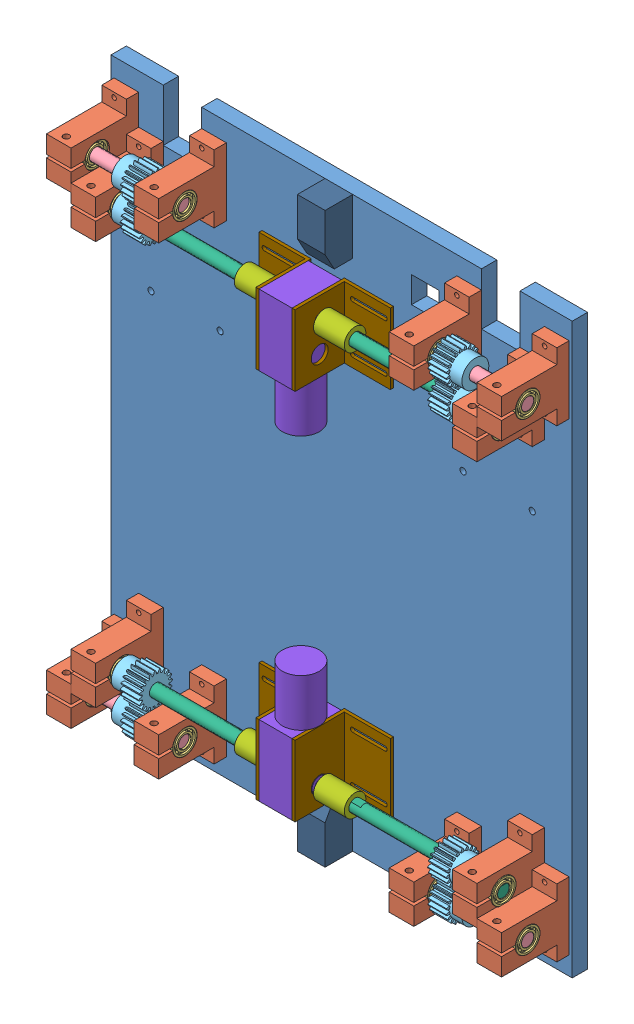
SolidWorks assembly 装配体1, configuration 默认. Lengths in mm.
Overall size (300 370 54).
64 component instances, 10 part files, 32 mates.
Components (placement in the parent):
- 坐垫-1: 坐垫 [默认] at (-124.3252 -195.4572 365) size (300 370 10)
- 光轴支架-1: 光轴支架 [默认] at (-142.3271 -143.8242 371.8767) x (0 -1 0) z (-1 0 0) size (44 44 16)
- deep groove ball bearings gb-1: deep groove ball bearings gb [Rolling bearings 618-8 GB 276-94] at (-145.2035 -140.9025 402) x (-1 0 0) z (0 -0.927196 -0.374576) size (4 16 16)
- am8-1: am8 [默认] at (-86.5971 -156.6197 405.6451) x (0 -0.279688 0.960091) z (-1 0 0) size (8 8 71.73)
- spur gear_gb-1: spur gear_gb [GB - Spur gear 1M 20T 20PA 12FW ---S20B75H20L8.0N] at (-116.3271 -140.9025 402) x (1 0 0) z (0 0.809131 -0.587628) size (20 21.8 21.8)
- 光轴支架-2: 光轴支架 [默认] at (-142.3271 -118.2309 371.8767) x (0 1 0) z (1 0 0) size (44 44 16)
- deep groove ball bearings gb-2: deep groove ball bearings gb [Rolling bearings 618-8 GB 276-94] at (-129.0651 -121.1525 402) size (4 16 16)
- M8光轴连接齿轮-1: M8光轴连接齿轮 [默认] at (-142.3271 -136.3515 404.7888) x (0 0 -1) z (1 0 0) size (8 8 104.25)
- deep groove ball bearings gb-3: deep groove ball bearings gb [Rolling bearings 618-8 GB 276-94] at (-140.8939 -121.1525 402) size (4 16 16)
- deep groove ball bearings gb-4: deep groove ball bearings gb [Rolling bearings 618-8 GB 276-94] at (-156.497 -140.9025 402) x (-1 0 0) z (0 -0.924225 -0.381849) size (4 16 16)
- 联轴器-1: 联轴器 [默认] at (-26.0771 -121.1525 402) x (0 0.642544 -0.766249) z (-1 0 0) size (14 14 20)
- 双输出涡轮蜗杆电机-1: 双输出涡轮蜗杆电机 [默认] at (-27.3331 -113.7996 418) x (0 1 0) z (0 0 -1) size (76.8 52.5 32)
- 零件1-1: 零件1 [默认] at (-21.0771 -118.3588 384) x (0 -1 0) z (-1 0 0) size (46 34 32)
- spur gear_gb-5: spur gear_gb [GB - Spur gear 1M 20T 20PA 12FW ---S20B75H20L8.0N] at (-116.3271 -121.1525 402) x (1 0 0) z (0 -0.733673 0.679503) size (20 21.8 21.8)
- 光轴支架-3: 光轴支架 [默认] at (-85.2921 -143.8242 371.8767) x (0 -1 0) z (-1 0 0) size (44 44 16)
- deep groove ball bearings gb-7: deep groove ball bearings gb [Rolling bearings 618-8 GB 276-94] at (-87.2921 -140.9025 402) x (-1 0 0) z (0 -0.924225 -0.381849) size (4 16 16)
- deep groove ball bearings gb-8: deep groove ball bearings gb [Rolling bearings 618-8 GB 276-94] at (-99.2921 -140.9025 402) size (4 16 16)
- 光轴支架-4: 光轴支架 [默认] at (137.6729 -143.8242 371.8767) x (0 -1 0) z (-1 0 0) size (44 44 16)
- deep groove ball bearings gb-9: deep groove ball bearings gb [Rolling bearings 618-8 GB 276-94] at (124.5493 -140.9025 402) x (1 0 0) z (0 0.927196 0.374576) size (4 16 16)
- deep groove ball bearings gb-10: deep groove ball bearings gb [Rolling bearings 618-8 GB 276-94] at (120.2398 -121.1525 402) x (-1 0 0) z (0 0 -1) size (4 16 16)
- am8-2: am8 [默认] at (137.6729 -156.6197 405.6451) x (0 -0.279688 0.960091) z (-1 0 0) size (8 8 71.73)
- spur gear_gb-2: spur gear_gb [GB - Spur gear 1M 20T 20PA 12FW ---S20B75H20L8.0N] at (95.6729 -140.9025 402) x (-1 0 0) z (0 -0.809131 0.587628) size (20 21.8 21.8)
- 光轴支架-5: 光轴支架 [默认] at (105.6729 -118.2309 371.8767) x (0 1 0) z (1 0 0) size (44 44 16)
- M8光轴连接齿轮-2: M8光轴连接齿轮 [默认] at (17.4229 -136.3515 404.7888) x (0 0 -1) z (1 0 0) size (8 8 104.25)
- deep groove ball bearings gb-11: deep groove ball bearings gb [Rolling bearings 618-8 GB 276-94] at (108.411 -121.1525 402) x (-1 0 0) z (0 0 -1) size (4 16 16)
- deep groove ball bearings gb-12: deep groove ball bearings gb [Rolling bearings 618-8 GB 276-94] at (135.8428 -140.9025 402) x (1 0 0) z (0 0.924225 0.381849) size (4 16 16)
- spur gear_gb-6: spur gear_gb [GB - Spur gear 1M 20T 20PA 12FW ---S20B75H20L8.0N] at (95.6729 -121.1525 402) x (-1 0 0) z (0 0.733673 -0.679503) size (20 21.8 21.8)
- deep groove ball bearings gb-13: deep groove ball bearings gb [Rolling bearings 618-8 GB 276-94] at (66.6379 -140.9025 402) x (1 0 0) z (0 0.924225 0.381849) size (4 16 16)
- 光轴支架-6: 光轴支架 [默认] at (80.6379 -143.8242 371.8767) x (0 -1 0) z (-1 0 0) size (44 44 16)
- deep groove ball bearings gb-14: deep groove ball bearings gb [Rolling bearings 618-8 GB 276-94] at (78.6379 -140.9025 402) x (-1 0 0) z (0 0 -1) size (4 16 16)
- 零件1-2: 零件1 [默认] at (0.4229 -103.9462 384) x (0 1 0) z (1 0 0) size (46 34 32)
- 联轴器-2: 联轴器 [默认] at (5.4229 -121.1525 402) x (0 -0.642544 0.766249) z (1 0 0) size (14 14 20)
- 光轴支架-13: 光轴支架 [默认] at (-158.3271 164.0191 371.8767) x (0 1 0) z (1 0 0) size (44 44 16)
- deep groove ball bearings gb-27: deep groove ball bearings gb [Rolling bearings 618-8 GB 276-94] at (-156.497 161.0975 402) x (-1 0 0) z (0 -0.924225 0.381849) size (4 16 16)
- deep groove ball bearings gb-28: deep groove ball bearings gb [Rolling bearings 618-8 GB 276-94] at (-145.2035 161.0975 402) x (-1 0 0) z (0 -0.927196 0.374576) size (4 16 16)
- am8-5: am8 [默认] at (-158.3271 176.8147 405.6451) x (0 0.279688 0.960091) z (1 0 0) size (8 8 71.73)
- 光轴支架-14: 光轴支架 [默认] at (-126.3271 138.4258 371.8767) x (0 -1 0) z (-1 0 0) size (44 44 16)
- deep groove ball bearings gb-29: deep groove ball bearings gb [Rolling bearings 618-8 GB 276-94] at (-140.8939 141.3475 402) x (1 0 0) z (0 0 -1) size (4 16 16)
- deep groove ball bearings gb-30: deep groove ball bearings gb [Rolling bearings 618-8 GB 276-94] at (-129.0651 141.3475 402) x (1 0 0) z (0 0 -1) size (4 16 16)
- spur gear_gb-9: spur gear_gb [GB - Spur gear 1M 20T 20PA 12FW ---S20B75H20L8.0N] at (-116.3271 141.3475 402) x (1 0 0) z (0 -0.733673 -0.679503) size (20 21.8 21.8)
- M8光轴连接齿轮-5: M8光轴连接齿轮 [默认] at (-38.0771 156.5465 404.7888) x (0 0 -1) z (-1 0 0) size (8 8 104.25)
- spur gear_gb-10: spur gear_gb [GB - Spur gear 1M 20T 20PA 12FW ---S20B75H20L8.0N] at (-116.3271 161.0975 402) x (1 0 0) z (0 0.809131 0.587628) size (20 21.8 21.8)
- 光轴支架-15: 光轴支架 [默认] at (-101.2921 164.0191 371.8767) x (0 1 0) z (1 0 0) size (44 44 16)
- deep groove ball bearings gb-31: deep groove ball bearings gb [Rolling bearings 618-8 GB 276-94] at (-99.2921 161.0975 402) x (1 0 0) z (0 0 -1) size (4 16 16)
- deep groove ball bearings gb-32: deep groove ball bearings gb [Rolling bearings 618-8 GB 276-94] at (-87.2921 161.0975 402) x (-1 0 0) z (0 -0.924225 0.381849) size (4 16 16)
- 零件1-5: 零件1 [默认] at (-21.0771 124.1412 384) x (0 -1 0) z (-1 0 0) size (46 34 32)
- 联轴器-5: 联轴器 [默认] at (-26.0771 141.3475 402) x (0 0.642544 0.766249) z (-1 0 0) size (14 14 20)
- 零件1-6: 零件1 [默认] at (0.4229 138.5538 384) x (0 1 0) z (1 0 0) size (46 34 32)
- 联轴器-6: 联轴器 [默认] at (5.4229 141.3475 402) x (0 -0.642544 -0.766249) z (1 0 0) size (14 14 20)
- M8光轴连接齿轮-6: M8光轴连接齿轮 [默认] at (121.6729 156.5465 404.7888) x (0 0 -1) z (-1 0 0) size (8 8 104.25)
- 光轴支架-16: 光轴支架 [默认] at (121.6729 138.4258 371.8767) x (0 -1 0) z (-1 0 0) size (44 44 16)
- spur gear_gb-11: spur gear_gb [GB - Spur gear 1M 20T 20PA 12FW ---S20B75H20L8.0N] at (95.6729 141.3475 402) x (-1 0 0) z (0 0.733673 0.679503) size (20 21.8 21.8)
- deep groove ball bearings gb-33: deep groove ball bearings gb [Rolling bearings 618-8 GB 276-94] at (108.411 141.3475 402) x (-1 0 0) z (0 0 1) size (4 16 16)
- deep groove ball bearings gb-34: deep groove ball bearings gb [Rolling bearings 618-8 GB 276-94] at (120.2398 141.3475 402) x (-1 0 0) z (0 0 1) size (4 16 16)
- am8-6: am8 [默认] at (65.9429 176.8147 405.6451) x (0 0.279688 0.960091) z (1 0 0) size (8 8 71.73)
- 光轴支架-17: 光轴支架 [默认] at (121.6729 164.0191 371.8767) x (0 1 0) z (1 0 0) size (44 44 16)
- 光轴支架-18: 光轴支架 [默认] at (64.6379 164.0191 371.8767) x (0 1 0) z (1 0 0) size (44 44 16)
- spur gear_gb-12: spur gear_gb [GB - Spur gear 1M 20T 20PA 12FW ---S20B75H20L8.0N] at (95.6729 161.0975 402) x (-1 0 0) z (0 -0.809131 -0.587628) size (20 21.8 21.8)
- deep groove ball bearings gb-35: deep groove ball bearings gb [Rolling bearings 618-8 GB 276-94] at (78.6379 161.0975 402) x (-1 0 0) z (0 0 1) size (4 16 16)
- deep groove ball bearings gb-36: deep groove ball bearings gb [Rolling bearings 618-8 GB 276-94] at (66.6379 161.0975 402) x (1 0 0) z (0 0.924225 -0.381849) size (4 16 16)
- 双输出涡轮蜗杆电机-3: 双输出涡轮蜗杆电机 [默认] at (-27.3331 133.9946 386) x (0 -1 0) z (0 0 1) size (76.8 52.5 32)
- deep groove ball bearings gb-37: deep groove ball bearings gb [Rolling bearings 618-8 GB 276-94] at (135.8428 161.0975 402) x (1 0 0) z (0 0.924225 -0.381849) size (4 16 16)
- 接近开关-1: 接近开关 [默认] at (-3.0771 -170.4461 383.327) x (0 -1 0) z (-1 0 0) size (36 18 18)
- 接近开关-2: 接近开关 [默认] at (-21.0771 190.6411 383.327) x (0 1 0) z (1 0 0) size (36 18 18)
Mates (geometry in assembly coordinates):
- 同心1: concentric anti-aligned: cylinder of 坐垫-1 through (-150.3271 -159.9025 365) axis (0 0 1) radius 1.5; cylinder of 光轴支架-1 through (-150.3271 -159.9025 414) axis (0 0 -1) radius 1.5
- 重合1: coincident anti-aligned: plane of 坐垫-1 through (-124.3252 -195.4572 375) normal (0 0 1); plane of 光轴支架-1 through (-158.3271 -118.9025 375) normal (0 0 -1)
- 同心21: concentric aligned: cylinder of 光轴支架-1 through (-158.3271 -140.9025 402) axis (1 0 0) radius 8; cylinder of deep groove ball bearings gb-1 through (-138.2321 -140.9025 402) axis (1 0 0) radius 4
- 同心3: concentric aligned: cylinder of deep groove ball bearings gb-1 through (-138.2321 -140.9025 402) axis (1 0 0) radius 4; cylinder of am8-1 through (-158.3271 -140.9025 402) axis (1 0 0) radius 4
- 同心4: concentric anti-aligned: cylinder of am8-1 through (-158.3271 -140.9025 402) axis (1 0 0) radius 4; cylinder of spur gear_gb-1 through (-96.327 -140.9025 402) axis (-1 0 0) radius 4
- 同心5: concentric anti-aligned: cylinder of 坐垫-1 through (-150.3271 -121.9025 365) axis (0 0 1) radius 1.5; cylinder of 光轴支架-1 through (-150.3271 -121.9025 414) axis (0 0 -1) radius 1.5
- 同心23: concentric anti-aligned: cylinder of 坐垫-1 through (-134.3271 -140.1525 365) axis (0 0 1) radius 1.5; cylinder of 光轴支架-2 through (-134.3271 -140.1525 414) axis (0 0 -1) radius 1.5
- 同心241: concentric aligned: cylinder of 光轴支架-2 through (-126.3271 -121.1525 402) axis (-1 0 0) radius 8; cylinder of deep groove ball bearings gb-2 through (-136.0365 -121.1525 402) axis (-1 0 0) radius 4
- 同心25: concentric aligned: cylinder of deep groove ball bearings gb-2 through (-136.0365 -121.1525 402) axis (-1 0 0) radius 4; cylinder of M8光轴连接齿轮-1 through (-38.0771 -121.1525 402) axis (-1 0 0) radius 4
- 重合5: coincident aligned: plane of 光轴支架-1 through (-158.3271 -143.8242 371.8767) normal (-1 0 0); plane of am8-1 through (-158.3271 -140.9025 402) normal (-1 0 0)
- 重合6: coincident aligned: plane of 光轴支架-2 through (-142.3271 -118.2309 371.8767) normal (-1 0 0); plane of M8光轴连接齿轮-1 through (-142.3271 -121.1525 402) normal (-1 0 0)
- 同心261: concentric aligned: cylinder of 光轴支架-2 through (-126.3271 -121.1525 402) axis (-1 0 0) radius 8; cylinder of deep groove ball bearings gb-3 through (-147.8653 -121.1525 402) axis (-1 0 0) radius 4
- 同心271: concentric aligned: cylinder of 光轴支架-1 through (-158.3271 -140.9025 402) axis (1 0 0) radius 8; cylinder of deep groove ball bearings gb-4 through (-149.5256 -140.9025 402) axis (1 0 0) radius 4
- 同心28: concentric aligned: cylinder of M8光轴连接齿轮-1 through (-38.0771 -121.1525 402) axis (-1 0 0) radius 4; cylinder of 联轴器-1 through (-38.0771 -121.1525 402) axis (-1 0 0) radius 4
- 重合7: coincident anti-aligned: plane of 坐垫-1 through (-124.3252 -195.4572 375) normal (0 0 1); plane of 光轴支架-2 through (-126.3271 -143.1525 375) normal (0 0 -1)
- 重合8: coincident anti-aligned: plane of 光轴支架-1 through (-142.3271 -143.8242 371.8767) normal (1 0 0); plane of 光轴支架-2 through (-142.3271 -118.2309 371.8767) normal (-1 0 0)
- 重合10: coincident anti-aligned: plane of 联轴器-1 through (-36.0771 -121.1525 402) normal (1 0 0); plane of 双输出涡轮蜗杆电机-1 through (-36.0771 -121.1525 402) normal (-1 0 0)
- 同心29: concentric aligned: cylinder of 联轴器-1 through (-36.0771 -121.1525 402) axis (1 0 0) radius 3; cylinder of 双输出涡轮蜗杆电机-1 through (-36.0771 -121.1525 402) axis (1 0 0) radius 3
- 重合11: coincident anti-aligned: plane of 双输出涡轮蜗杆电机-1 through (-21.0771 -134.1525 386) normal (-1 0 0); plane of 零件1-1 through (-21.0771 -118.3588 384) normal (1 0 0)
- 同心311: concentric aligned: cylinder of M8光轴连接齿轮-1 through (-38.0771 -121.1525 402) axis (-1 0 0) radius 4; cylinder of spur gear_gb-5 through (-96.327 -121.1525 402) axis (-1 0 0) radius 4
- 重合12: coincident aligned: plane of spur gear_gb-1 through (-104.3271 -140.9025 402) normal (1 0 0); plane of spur gear_gb-5 through (-104.3271 -121.1525 402) normal (1 0 0)
- 同心32: concentric aligned: cylinder of 光轴支架-1 through (-158.3271 -140.9025 402) axis (1 0 0) radius 8; cylinder of 光轴支架-3 through (-101.2921 -140.9025 402) axis (1 0 0) radius 8
- 重合15: coincident aligned: plane of 光轴支架-1 through (-158.3271 -162.9025 375) normal (0 -1 0); plane of 光轴支架-3 through (-101.2921 -162.9025 375) normal (0 -1 0)
- 同心33: concentric aligned: cylinder of am8-1 through (-158.3271 -140.9025 402) axis (1 0 0) radius 4; cylinder of deep groove ball bearings gb-7 through (-80.3207 -140.9025 402) axis (1 0 0) radius 4
- 重合16: coincident aligned: plane of 光轴支架-3 through (-85.2921 -143.8242 371.8767) normal (1 0 0); plane of deep groove ball bearings gb-7 through (-85.2921 -137.8477 394.6062) normal (1 0 0)
- 同心35: concentric anti-aligned: cylinder of am8-1 through (-158.3271 -140.9025 402) axis (1 0 0) radius 4; cylinder of deep groove ball bearings gb-8 through (-106.2634 -140.9025 402) axis (-1 0 0) radius 4
- 重合19: coincident aligned: plane of 光轴支架-3 through (-101.2921 -143.8242 371.8767) normal (-1 0 0); plane of deep groove ball bearings gb-8 through (-101.2921 -132.9025 402) normal (-1 0 0)
- 重合64: coincident: plane of 坐垫-1 through (-160.3271 -174.9025 375) normal (0 -1 0); plane of 接近开关-1 through (-21.0771 -174.9025 375) normal (0 -1 0)
- 平行3: parallel: plane of 双输出涡轮蜗杆电机-1 through (0.4229 -88.1525 386) normal (1 0 0); plane of 零件1-2 through (0.4229 -103.9462 384) normal (-1 0 0)
- 重合65: coincident: plane of 双输出涡轮蜗杆电机-1 through (-21.0771 -134.1525 386) normal (-1 0 0); plane of 接近开关-1 through (-21.0771 -170.4461 383.327) normal (-1 0 0)
- 重合66: coincident: plane of 坐垫-1 through (-124.3252 -195.4572 375) normal (0 0 1); plane of 接近开关-1 through (-21.0771 -168.9025 375) normal (0 0 -1)
- 重合67: coincident anti-aligned: plane of 双输出涡轮蜗杆电机-1 through (0.4229 -88.1525 386) normal (1 0 0); plane of 零件1-2 through (0.4229 -103.9462 384) normal (-1 0 0)
